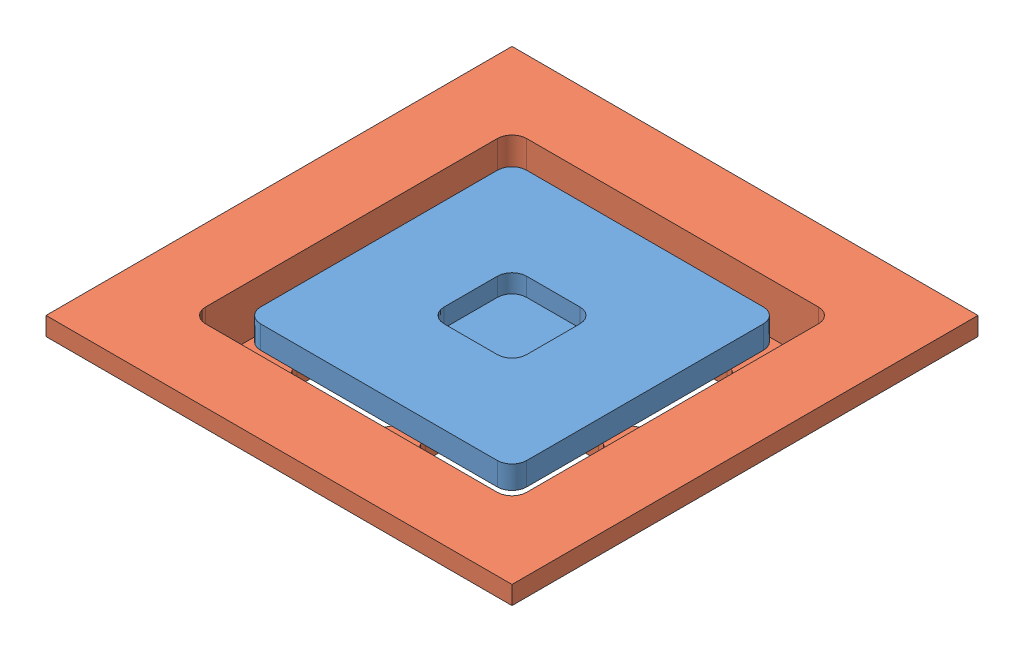
SolidWorks assembly Tower Cap ASM, configuration Default. Lengths in mm.
Overall size (50.8 7.5 50.8).
2 component instances, 2 part files, 3 mates.
Components (placement in the parent):
- Tower Cap - 01-1: Tower Cap - 01 [Default] at (12.9 178.5 -12.9) size (29 7.5 29)
- Tower Cap - 02-2: Tower Cap - 02 [Default] at (3.5875 178.4992 -3.5875) size (50.8 7.5 50.8)
Mates (geometry in assembly coordinates):
- Width11: width anti-aligned: plane of Tower Cap - 02-2 through (9.9 186 -44.9) normal (1 0 0); plane of Tower Cap - 02-2 through (44.9 186 -44.9) normal (-1 0 0); plane of Tower Cap - 01-1 through (12.9 186 -12.9) normal (-1 0 0); plane of Tower Cap - 01-1 through (41.9 186 -12.9) normal (1 0 0)
- Width12: width aligned: plane of Tower Cap - 01-1 through (12.9 186 -41.9) normal (0 0 -1); plane of Tower Cap - 01-1 through (12.9 186 -12.9) normal (0 0 1); plane of Tower Cap - 02-2 through (9.9 186 -9.9) normal (0 0 -1); plane of Tower Cap - 02-2 through (9.9 186 -44.9) normal (0 0 1)
- Coincident2: coincident aligned: plane of Tower Cap - 01-1 through (12.9 186 -12.9) normal (0 1 0); plane of Tower Cap - 03-1 through (3.5875 186 -3.5875) normal (0 1 0)
